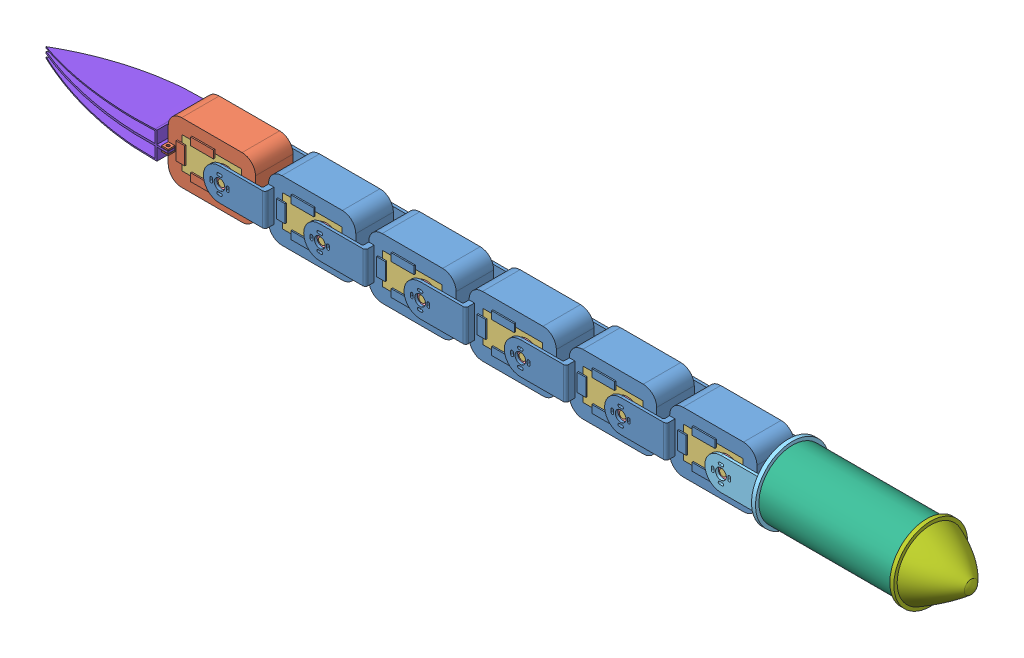
SolidWorks assembly bus_assembly_3, configuration 預設. Lengths in mm.
Overall size (691.28 55 144.5).
28 component instances, 8 part files, 89 mates.
Components (placement in the parent):
- bus2-1: bus2 [預設] at (12.4546 -2.1213 92.75) size (107 45 40.5)
- bus2-2: bus2 [預設] at (-62.2454 -2.1213 92.75) size (107 45 40.5)
- bus2-3: bus2 [預設] at (-286.3454 -2.1213 92.75) size (107 45 40.5)
- bus2-4: bus2 [預設] at (-136.9454 -2.1213 92.75) size (107 45 40.5)
- bus2-5: bus2 [預設] at (-211.6454 -2.1213 92.75) size (107 45 40.5)
- bus2_tail-1: bus2_tail [預設] at (-361.0454 -2.1213 92.75) size (65 45 38)
- bus_servo-1: bus_servo [預設] at (-368.5322 -13.6144 92.75) x (1 0 0) z (0 -1 0) size (44.4 38 23.4)
- bus_servo_cicrcle1-1: bus_servo_cicrcle1 [預設] at (-376.28 -2.2213 122.25) size (20 20 3)
- bus_servo_cicrcle1-2: bus_servo_cicrcle1 [預設] at (-376.28 -2.1213 88.75) size (20 20 3)
- bus_servo-2: bus_servo [預設] at (-293.8322 -13.6144 92.75) x (1 0 0) z (0 -1 0) size (44.4 38 23.4)
- bus_servo-3: bus_servo [預設] at (-219.1322 -13.6144 92.75) x (1 0 0) z (0 -1 0) size (44.4 38 23.4)
- bus_servo-4: bus_servo [預設] at (-144.4322 9.3718 120.75) x (1 0 0) z (0 1 0) size (44.4 38 23.4)
- bus_servo-5: bus_servo [預設] at (-69.7322 -13.6144 92.75) x (1 0 0) z (0 -1 0) size (44.4 38 23.4)
- bus_servo-6: bus_servo [預設] at (4.9678 -13.6144 92.75) x (1 0 0) z (0 -1 0) size (44.4 38 23.4)
- bus_servo_cicrcle1-3: bus_servo_cicrcle1 [預設] at (-301.58 -2.1213 122.25) size (20 20 3)
- bus_servo_cicrcle1-4: bus_servo_cicrcle1 [預設] at (-301.58 -2.1213 88.75) size (20 20 3)
- bus_servo_cicrcle1-5: bus_servo_cicrcle1 [預設] at (-226.88 -2.1213 88.75) size (20 20 3)
- bus_servo_cicrcle1-6: bus_servo_cicrcle1 [預設] at (-226.88 -2.1213 122.25) size (20 20 3)
- bus_servo_cicrcle1-7: bus_servo_cicrcle1 [預設] at (-152.18 -2.1213 122.25) size (20 20 3)
- bus_servo_cicrcle1-8: bus_servo_cicrcle1 [預設] at (-152.18 -2.1213 88.75) size (20 20 3)
- bus_servo_cicrcle1-9: bus_servo_cicrcle1 [預設] at (-77.48 -2.1213 122.25) size (20 20 3)
- bus_servo_cicrcle1-10: bus_servo_cicrcle1 [預設] at (-77.48 -2.1213 88.75) size (20 20 3)
- bus_servo_cicrcle1-11: bus_servo_cicrcle1 [預設] at (-2.78 -2.1213 88.75) size (20 20 3)
- bus_servo_cicrcle1-12: bus_servo_cicrcle1 [預設] at (-2.78 -2.1213 122.25) x (0 1 0) z (0 0 1) size (20 20 3)
- bus_lib_tail-1: bus_lib_tail [預設] at (30.22 -2.1213 107) x (0 1 0) z (0 0 -1) size (55 65 55)
- bus_body-1: bus_body [預設] at (30.22 -2.1213 107) x (0 -0.027366 -0.999625) z (0 -0.999625 0.027366) size (50 100 50)
- bus_lib_head_1-1: bus_lib_head_1 [預設] at (130.22 -2.1213 107) x (0 1 0) z (0 0 1) size (55 54.98 55)
- bus_final_tail-2: bus_final_tail [預設] at (-425.0707 -2.1213 107.4806) x (-1 0 -0.00071) z (0 -1 0) size (110.1 38.13 25.31)
Mates (geometry in assembly coordinates):
- 重合/共線/共點1: coincident: plane of bus2-1 through (12.4546 -2.1213 120.75) normal (0 0 1); plane of bus2-2 through (-62.2454 -2.1213 120.75) normal (0 0 1)
- 重合/共線/共點2: coincident: plane of bus2-1 through (-47.48 20.3787 120.75) normal (0 1 0); plane of bus2-2 through (-122.18 20.3787 120.75) normal (0 1 0)
- 重合/共線/共點3: coincident: plane of bus2-3 through (-286.3454 -2.1213 120.75) normal (0 0 1); plane of bus2-2 through (-62.2454 -2.1213 120.75) normal (0 0 1)
- 重合/共線/共點4: coincident: plane of bus2-2 through (-122.18 20.3787 120.75) normal (0 1 0); plane of bus2-3 through (-346.28 20.3787 120.75) normal (0 1 0)
- 重合/共線/共點5: coincident: plane of bus2-3 through (-346.28 20.3787 120.75) normal (0 1 0); plane of bus2-4 through (-196.88 20.3787 120.75) normal (0 1 0)
- 重合/共線/共點6: coincident: plane of bus2-3 through (-286.3454 -2.1213 120.75) normal (0 0 1); plane of bus2-4 through (-136.9454 -2.1213 120.75) normal (0 0 1)
- 重合/共線/共點9: coincident: plane of bus2-3 through (-346.28 20.3787 120.75) normal (0 1 0); plane of bus2-5 through (-271.58 20.3787 120.75) normal (0 1 0)
- 重合/共線/共點10: coincident: plane of bus2-3 through (-286.3454 -2.1213 120.75) normal (0 0 1); plane of bus2-5 through (-211.6454 -2.1213 120.75) normal (0 0 1)
- 重合/共線/共點11: coincident: plane of bus2-3 through (-286.3454 -2.1213 120.75) normal (0 0 1); plane of bus2_tail-1 through (-361.0454 -2.1213 120.75) normal (0 0 1)
- 重合/共線/共點12: coincident: plane of bus2-3 through (-346.28 20.3787 120.75) normal (0 1 0); plane of bus2_tail-1 through (-420.98 20.3787 120.75) normal (0 1 0)
- 同軸心1: concentric: cylinder of bus2_tail-1 through (-418.48 2.8787 123.25) axis (0 -1 0) radius 1.1; cylinder of ? through (-418.48 -1.3713 123.25) axis (0 -1 0) radius 1.1
- 同軸心2: concentric: cylinder of bus2_tail-1 through (-418.48 2.8787 90.25) axis (0 -1 0) radius 1.1; cylinder of ? through (-418.48 -1.3713 90.25) axis (0 -1 0) radius 1.1
- 平行相距1: distance = 0.25 mm: line of ? through (-415.9818 -1.3713 125.7518) axis (-1 0 -0.00071); line of bus2_tail-1 through (-420.98 -1.1213 125.75) axis (1 0 0)
- 重合/共線/共點13: coincident: plane of bus2_tail-1 through (-410.68 -13.8213 131.75) normal (0 1 0); plane of bus_servo-1 through (-410.68 -13.8213 120.75) normal (0 -1 0)
- 重合/共線/共點14: coincident: plane of bus2_tail-1 through (-366.28 9.5787 131.75) normal (-1 0 0); plane of bus_servo-1 through (-366.28 9.5787 120.75) normal (1 0 0)
- 重合/共線/共點17: coincident: plane of bus2_tail-1 through (-361.0454 -2.1213 120.75) normal (0 0 1); plane of bus_servo-1 through (-368.5322 -13.6144 120.75) normal (0 0 1)
- 重合/共線/共點18: coincident: plane of bus2-3 through (-377.33 2.9787 86.75) normal (0 1 0); plane of bus_servo_cicrcle1-1 through (-377.33 2.9787 126.25) normal (0 1 0)
- 平行2: parallel: plane of bus2-3 through (-377.33 -9.3213 86.75) normal (0 1 0); plane of bus_servo_cicrcle1-1 through (-377.33 -9.4213 126.25) normal (0 1 0)
- 重合/共線/共點21: coincident: plane of bus2-3 through (-383.48 -1.0713 86.75) normal (1 0 0); plane of bus_servo_cicrcle1-1 through (-383.48 -1.1713 126.25) normal (1 0 0)
- 平行3: parallel: cylinder of bus2-3 through (-376.28 -2.1213 125.25) axis (0 0 1) radius 4; cylinder of bus_servo_cicrcle1-1 through (-376.28 -2.2213 126.25) axis (0 0 -1) radius 4
- 重合/共線/共點22: coincident: plane of bus2-3 through (-376.28 -2.1213 125.25) normal (0 0 -1); plane of bus_servo_cicrcle1-1 through (-376.28 -2.2213 125.25) normal (0 0 1)
- 重合/共線/共點23: coincident: plane of bus2-3 through (-376.28 -2.1213 88.75) normal (0 0 1); plane of bus_servo_cicrcle1-2 through (-376.28 -2.1213 88.75) normal (0 0 -1)
- 同軸心5: concentric: cylinder of bus2-3 through (-376.28 -2.1213 86.75) axis (0 0 1) radius 3.7; cylinder of bus_servo_cicrcle1-2 through (-376.28 -2.1213 92.75) axis (0 0 -1) radius 4
- 同軸心8: concentric: cylinder of bus2-3 through (-376.28 -2.1213 86.75) axis (0 0 1) radius 3.7; cylinder of bus_servo-1 through (-376.28 -2.1213 87.75) axis (0 0 1) radius 2.5
- 重合/共線/共點24: coincident: plane of bus2-3 through (-335.98 -13.8213 131.75) normal (0 1 0); plane of bus_servo-2 through (-335.98 -13.8213 120.75) normal (0 -1 0)
- 重合/共線/共點25: coincident: plane of bus2-3 through (-335.98 9.5787 131.75) normal (1 0 0); plane of bus_servo-2 through (-335.98 9.5787 120.75) normal (-1 0 0)
- 重合/共線/共點26: coincident: plane of bus2-3 through (-286.3454 -2.1213 92.75) normal (0 0 -1); plane of bus_servo-2 through (-293.8322 -13.6144 92.75) normal (0 0 -1)
- 重合/共線/共點27: coincident: plane of bus2-5 through (-261.28 -13.8213 131.75) normal (0 1 0); plane of bus_servo-3 through (-261.28 -13.8213 120.75) normal (0 -1 0)
- 重合/共線/共點28: coincident: plane of bus2-5 through (-261.28 9.5787 131.75) normal (1 0 0); plane of bus_servo-3 through (-261.28 9.5787 120.75) normal (-1 0 0)
- 重合/共線/共點29: coincident: plane of bus2-5 through (-211.6454 -2.1213 92.75) normal (0 0 -1); plane of bus_servo-3 through (-219.1322 -13.6144 92.75) normal (0 0 -1)
- 重合/共線/共點30: coincident: plane of bus2-2 through (-111.88 9.5787 131.75) normal (0 -1 0); plane of bus_servo-4 through (-186.58 9.5787 92.75) normal (0 1 0)
- 重合/共線/共點31: coincident: plane of bus2-4 through (-142.18 9.5787 131.75) normal (-1 0 0); plane of bus_servo-4 through (-142.18 -13.8213 92.75) normal (1 0 0)
- 重合/共線/共點32: coincident: plane of bus2-4 through (-136.9454 -2.1213 120.75) normal (0 0 1); plane of bus_servo-4 through (-144.4322 9.3718 120.75) normal (0 0 1)
- 重合/共線/共點37: coincident: plane of bus2-2 through (-111.88 9.5787 131.75) normal (0 -1 0); plane of bus_servo-5 through (-111.88 9.5787 120.75) normal (0 1 0)
- 重合/共線/共點38: coincident: plane of bus2-2 through (-67.48 9.5787 131.75) normal (-1 0 0); plane of bus_servo-5 through (-67.48 9.5787 120.75) normal (1 0 0)
- 重合/共線/共點40: coincident: plane of bus2-2 through (-62.2454 -2.1213 120.75) normal (0 0 1); plane of bus_servo-5 through (-69.7322 -13.6144 120.75) normal (0 0 1)
- 重合/共線/共點42: coincident: plane of bus2-1 through (12.4546 -2.1213 120.75) normal (0 0 1); plane of bus_servo-6 through (4.9678 -13.6144 120.75) normal (0 0 1)
- 重合/共線/共點43: coincident: plane of bus2-1 through (-37.18 9.5787 131.75) normal (1 0 0); plane of bus_servo-6 through (-37.18 9.5787 120.75) normal (-1 0 0)
- 重合/共線/共點44: coincident: plane of bus2-1 through (-37.18 9.5787 131.75) normal (0 -1 0); plane of bus_servo-6 through (-37.18 9.5787 120.75) normal (0 1 0)
- 同軸心9: concentric: cylinder of bus2-5 through (-301.58 -2.1213 125.25) axis (0 0 1) radius 4; cylinder of bus_servo_cicrcle1-3 through (-301.58 -2.1213 126.25) axis (0 0 -1) radius 4
- 重合/共線/共點45: coincident: plane of bus2-5 through (-301.58 -2.1213 125.25) normal (0 0 -1); plane of bus_servo_cicrcle1-3 through (-301.58 -2.1213 125.25) normal (0 0 1)
- 同軸心10: concentric: cylinder of bus2-5 through (-301.58 -2.1213 86.75) axis (0 0 1) radius 3.7; cylinder of bus_servo_cicrcle1-4 through (-301.58 -2.1213 92.75) axis (0 0 -1) radius 4
- 重合/共線/共點46: coincident: plane of bus2-5 through (-301.58 -2.1213 88.75) normal (0 0 1); plane of bus_servo_cicrcle1-4 through (-301.58 -2.1213 88.75) normal (0 0 -1)
- 同軸心11: concentric: cylinder of bus2-4 through (-226.88 -2.1213 125.25) axis (0 0 1) radius 4; cylinder of bus_servo_cicrcle1-6 through (-226.88 -2.1213 126.25) axis (0 0 -1) radius 4
- 重合/共線/共點47: coincident: plane of bus2-4 through (-226.88 -2.1213 125.25) normal (0 0 -1); plane of bus_servo_cicrcle1-6 through (-226.88 -2.1213 125.25) normal (0 0 1)
- 同軸心12: concentric: cylinder of bus2-4 through (-226.88 -2.1213 86.75) axis (0 0 1) radius 3.7; cylinder of bus_servo_cicrcle1-5 through (-226.88 -2.1213 92.75) axis (0 0 -1) radius 4
- 重合/共線/共點48: coincident: plane of bus2-4 through (-226.88 -2.1213 88.75) normal (0 0 1); plane of bus_servo_cicrcle1-5 through (-226.88 -2.1213 88.75) normal (0 0 -1)
- 同軸心13: concentric: cylinder of bus2-2 through (-152.18 -2.1213 86.75) axis (0 0 1) radius 3.7; cylinder of bus_servo_cicrcle1-8 through (-152.18 -2.1213 92.75) axis (0 0 -1) radius 4
- 重合/共線/共點49: coincident: plane of bus2-2 through (-152.18 -2.1213 88.75) normal (0 0 1); plane of bus_servo_cicrcle1-8 through (-152.18 -2.1213 88.75) normal (0 0 -1)
- 同軸心14: concentric: cylinder of bus2-2 through (-152.18 -2.1213 125.25) axis (0 0 1) radius 4; cylinder of bus_servo_cicrcle1-7 through (-152.18 -2.1213 126.25) axis (0 0 -1) radius 4
- 重合/共線/共點51: coincident: plane of bus2-2 through (-152.18 -2.1213 125.25) normal (0 0 -1); plane of bus_servo_cicrcle1-7 through (-152.18 -2.1213 125.25) normal (0 0 1)
- 重合/共線/共點52: coincident: plane of bus2-5 through (-302.63 -9.3213 125.25) normal (0 1 0); plane of bus_servo_cicrcle1-3 through (-302.63 -9.3213 126.25) normal (0 1 0)
- 平行6: parallel: plane of bus2-5 through (-294.48 -1.0713 125.25) normal (-1 0 0); plane of bus_servo_cicrcle1-3 through (-294.38 -1.0713 126.25) normal (-1 0 0)
- 平行8: parallel: plane of bus2-4 through (-219.78 -1.0713 125.25) normal (-1 0 0); plane of bus_servo_cicrcle1-6 through (-219.68 -1.0713 126.25) normal (-1 0 0)
- 重合/共線/共點56: coincident: plane of bus2-4 through (-227.93 -9.3213 125.25) normal (0 1 0); plane of bus_servo_cicrcle1-6 through (-227.93 -9.3213 126.25) normal (0 1 0)
- 平行9: parallel: plane of bus2-4 through (-219.78 -1.0713 86.75) normal (-1 0 0); plane of bus_servo_cicrcle1-5 through (-219.68 -1.0713 92.75) normal (-1 0 0)
- 平行10: parallel: plane of bus2-4 through (-227.93 4.9787 86.75) normal (0 -1 0); plane of bus_servo_cicrcle1-5 through (-227.93 5.0787 92.75) normal (0 -1 0)
- 平行11: parallel: line of bus2-2 through (-153.23 2.9787 127.25) axis (1 0 0); plane of bus_servo_cicrcle1-7 through (-153.23 3.0787 126.25) normal (0 1 0)
- 平行12: parallel: plane of bus2-2 through (-145.08 -1.0713 125.25) normal (-1 0 0); plane of bus_servo_cicrcle1-7 through (-144.98 -1.0713 126.25) normal (-1 0 0)
- 重合/共線/共點61: coincident: plane of bus2-2 through (-153.23 -7.3213 86.75) normal (0 -1 0); plane of bus_servo_cicrcle1-8 through (-153.23 -7.3213 92.75) normal (0 -1 0)
- 平行13: parallel: plane of bus2-2 through (-145.08 -1.0713 86.75) normal (-1 0 0); plane of bus_servo_cicrcle1-8 through (-144.98 -1.0713 92.75) normal (-1 0 0)
- 重合/共線/共點63: coincident: plane of bus2-1 through (-77.48 -2.1213 88.75) normal (0 0 1); plane of bus_servo_cicrcle1-10 through (-77.48 -2.1213 88.75) normal (0 0 -1)
- 同軸心15: concentric: cylinder of bus2-1 through (-77.48 -2.1213 86.75) axis (0 0 1) radius 3.7; cylinder of bus_servo_cicrcle1-10 through (-77.48 -2.1213 92.75) axis (0 0 -1) radius 4
- 平行14: parallel: plane of bus2-1 through (-78.53 2.9787 86.75) normal (0 1 0); plane of bus_servo_cicrcle1-10 through (-78.53 3.0787 92.75) normal (0 1 0)
- 同軸心16: concentric: cylinder of bus2-1 through (-77.48 -2.1213 125.25) axis (0 0 1) radius 4; cylinder of bus_servo_cicrcle1-9 through (-77.48 -2.1213 126.25) axis (0 0 -1) radius 4
- 重合/共線/共點65: coincident: plane of bus2-1 through (-77.48 -2.1213 125.25) normal (0 0 -1); plane of bus_servo_cicrcle1-9 through (-77.48 -2.1213 125.25) normal (0 0 1)
- 平行15: parallel: plane of bus2-1 through (-78.53 2.9787 125.25) normal (0 1 0); plane of bus_servo_cicrcle1-9 through (-78.53 3.0787 126.25) normal (0 1 0)
- 同軸心17: concentric: cylinder of bus_servo-2 through (-301.58 -2.1213 120.75) axis (0 0 1) radius 2.5; cylinder of bus_servo_cicrcle1-3 through (-301.58 -2.1213 126.25) axis (0 0 -1) radius 4
- 同軸心18: concentric: cylinder of bus_servo-3 through (-226.88 -2.1213 120.75) axis (0 0 1) radius 2.5; cylinder of bus_servo_cicrcle1-6 through (-226.88 -2.1213 126.25) axis (0 0 -1) radius 4
- 同軸心37: concentric: cylinder of bus_servo-4 through (-152.18 -2.1213 125.75) axis (0 0 -1) radius 2.5; cylinder of bus_servo_cicrcle1-7 through (-152.18 -2.1213 126.25) axis (0 0 -1) radius 4
- 同軸心39: concentric: cylinder of bus_servo-5 through (-77.48 -2.1213 87.75) axis (0 0 1) radius 2.5; cylinder of bus_servo_cicrcle1-10 through (-77.48 -2.1213 92.75) axis (0 0 -1) radius 4
- 重合/共線/共點76: coincident: plane of bus_servo_cicrcle1-12 through (-2.78 -2.1213 125.25) normal (0 0 1); plane of bus_lib_tail-1 through (-2.78 -2.1213 125.25) normal (0 0 -1)
- 重合/共線/共點77: coincident: plane of bus_servo_cicrcle1-11 through (-2.78 -2.1213 88.75) normal (0 0 -1); plane of bus_lib_tail-1 through (-2.78 -2.1213 88.75) normal (0 0 1)
- 同軸心41: concentric: cylinder of bus_servo_cicrcle1-11 through (-2.78 -2.1213 92.75) axis (0 0 -1) radius 4; cylinder of bus_lib_tail-1 through (-2.78 -2.1213 88.75) axis (0 0 -1) radius 4
- 重合/共線/共點78: coincident: plane of bus_servo_cicrcle1-11 through (-7.98 -1.0713 92.75) normal (-1 0 0); plane of bus_lib_tail-1 through (-7.98 -3.1713 88.75) normal (-1 0 0)
- 重合/共線/共點79: coincident: plane of bus_servo_cicrcle1-11 through (-3.83 -9.3213 92.75) normal (0 1 0); plane of bus_lib_tail-1 through (-1.73 -9.3213 88.75) normal (0 1 0)
- 重合/共線/共點80: coincident: plane of bus_servo_cicrcle1-12 through (-3.83 -9.3213 126.25) normal (0 1 0); plane of bus_lib_tail-1 through (-1.73 -9.3213 127.25) normal (0 1 0)
- 重合/共線/共點81: coincident: plane of bus_servo_cicrcle1-12 through (4.42 -3.1713 126.25) normal (-1 0 0); plane of bus_lib_tail-1 through (4.42 -3.1713 127.25) normal (-1 0 0)
- 同軸心42: concentric: cylinder of bus_servo_cicrcle1-12 through (-2.78 -2.1213 126.25) axis (0 0 -1) radius 4; cylinder of bus_lib_tail-1 through (-2.78 -2.1213 127.25) axis (0 0 -1) radius 4
- 同軸心43: concentric: cylinder of bus_servo-6 through (-2.78 -2.1213 120.75) axis (0 0 1) radius 2.5; cylinder of bus_servo_cicrcle1-12 through (-2.78 -2.1213 126.25) axis (0 0 -1) radius 4
- 重合/共線/共點82: coincident: plane of bus2-1 through (-47.48 9.8787 126.75) normal (0 1 0); plane of bus_lib_tail-1 through (27.22 9.8787 127.25) normal (0 1 0)
- 重合/共線/共點83: coincident: plane of bus2-1 through (-77.48 -2.1213 127.25) normal (0 0 1); plane of bus_lib_tail-1 through (-2.78 -2.1213 127.25) normal (0 0 1)
- 同軸心44: concentric: cylinder of bus_lib_tail-1 through (35.22 -2.1213 107) axis (1 0 0) radius 21.75; cylinder of bus_body-1 through (130.22 -2.1213 107) axis (-1 0 0) radius 22
- 重合/共線/共點84: coincident: plane of bus_lib_tail-1 through (30.22 -2.1213 107) normal (1 0 0); plane of bus_body-1 through (30.22 -2.1213 107) normal (-1 0 0)
- 同軸心45: concentric: cylinder of bus_body-1 through (130.22 -2.1213 107) axis (-1 0 0) radius 22; cylinder of bus_lib_head_1-1 through (115.72 -2.1213 107) axis (1 0 0) radius 21.75
- 重合/共線/共點85: coincident: plane of bus_body-1 through (130.22 -2.1213 107) normal (1 0 0); plane of bus_lib_head_1-1 through (130.22 -2.1213 107) normal (-1 0 0)
- 同軸心46: concentric: cylinder of bus2_tail-1 through (-418.48 2.8787 123.25) axis (0 -1 0) radius 1.1; cylinder of bus_final_tail-2 through (-418.48 -1.3713 123.25) axis (0 -1 0) radius 1.1
- 同軸心47: concentric: cylinder of bus2_tail-1 through (-418.48 2.8787 90.25) axis (0 -1 0) radius 1.1; cylinder of bus_final_tail-2 through (-418.48 -1.3713 90.25) axis (0 -1 0) radius 1.1
- 平行相距2: distance = 0.25 mm: plane of bus_final_tail-2 through (-425.0707 -1.3713 107.4806) normal (0 1 0); plane of bus2_tail-1 through (-361.0454 -1.1213 92.75) normal (0 -1 0)
